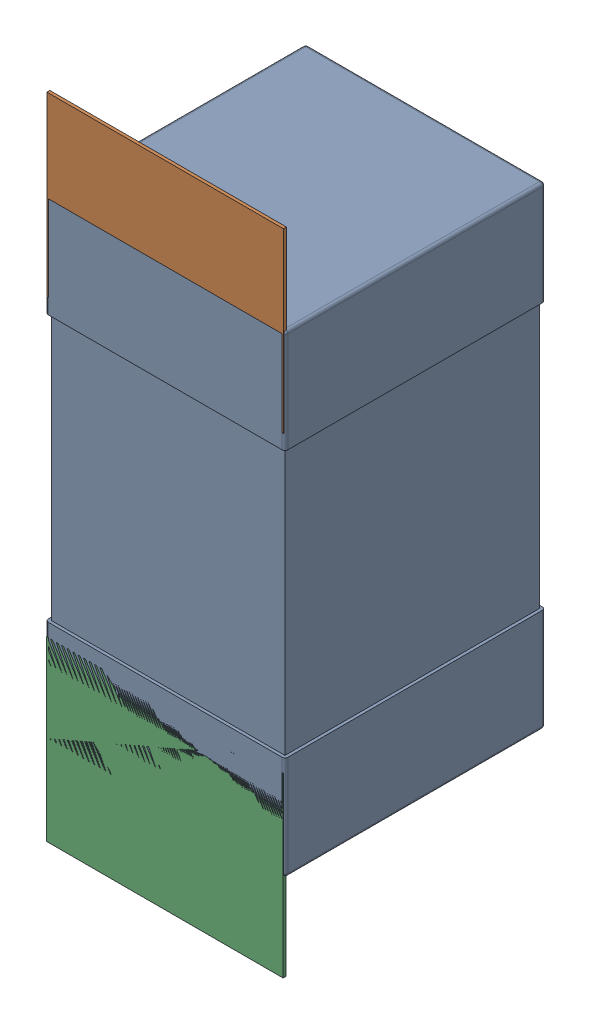
SolidWorks assembly C46, configuration Défaut. Lengths in mm.
Overall size (0.81 2.19 0.88).
5 component instances, 2 part files, 0 mates.
Components (placement in the parent):
- 0603_C-1: 0603_C [Défaut] at (17.1176 -9.3782 -2.0818) x (0 1 0) z (0 0 -1) size (1.6 0.81 0.88)
- 8260087904-1: 8260087904 [Défaut] at (17.1176 -8.1282 -2.0918) size (0.8 0.6 0.01)
  - Extruded_1211-1: Extruded_1211 [Défaut] at origin size (0.8 0.6 0.01)
- 8260087904-2: 8260087904 [Défaut] at (17.1163 -9.7231 -2.0918) size (0.8 0.6 0.01)
  - Extruded_1211-1: Extruded_1211 [Défaut] at origin size (0.8 0.6 0.01)
